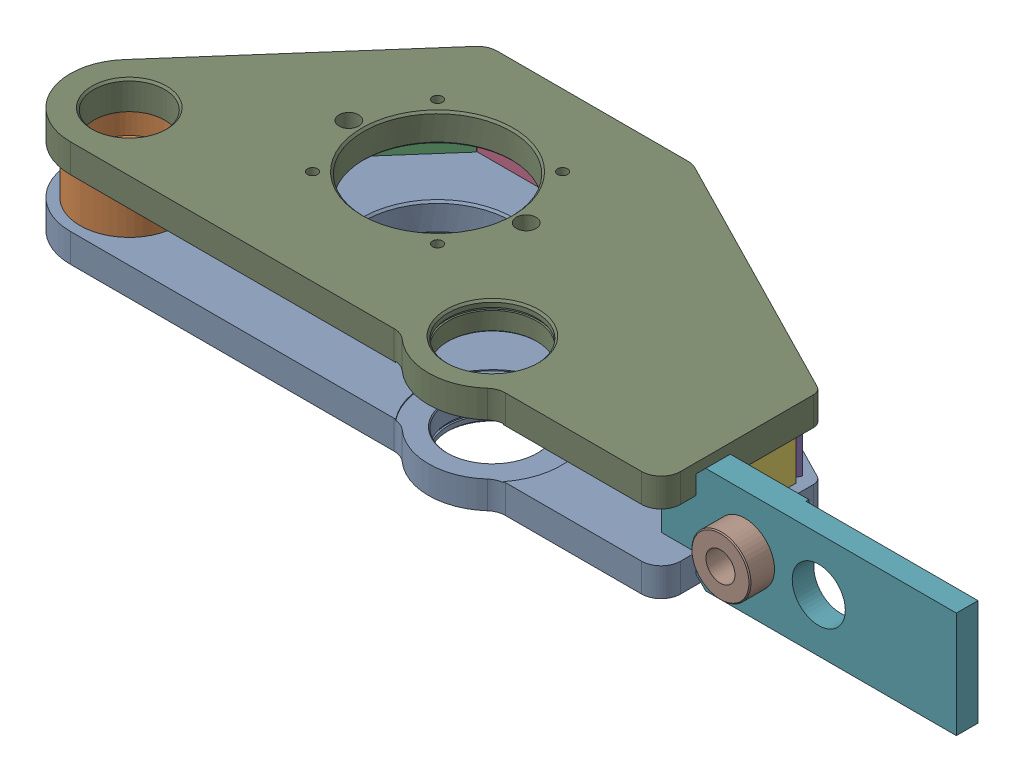
SolidWorks assembly g1_3_1_1_5_1, configuration 默认. Lengths in mm.
Overall size (926 108 318.6).
9 component instances, 9 part files, 0 mates.
Components (placement in the parent):
- g1_3_1_1_5-1_af1_1-1: g1_3_1_1_5-1_af1_1 [默认] at origin size (661 29 318.6)
- g1_3_1_1_5-2_af0_1-1: g1_3_1_1_5-2_af0_1 [默认] at (-213.2 29 0) size (100 50 100)
- g1_3_1_1_5-4_1-1: g1_3_1_1_5-4_1 [默认] at (-149.9151 54 -132.7301) x (0 1 0) z (-0.659692 0 0.751536) size (50 10 223)
- g1_3_1_1_5-5_1-1: g1_3_1_1_5-5_1 [默认] at (20.5 54 -217) x (1 0 0) z (0 1 0) size (194 10 50)
- g1_3_1_1_5-6_1-1: g1_3_1_1_5-6_1 [默认] at (248.4498 54 -161.5242) x (0 1 0) z (0.890083 0 0.455798) size (50 10 284)
- g1_3_1_1_5-7_1-1: g1_3_1_1_5-7_1 [默认] at (377.8 54 -43.9) x (0 0 -1) z (0 1 0) size (87 10 50)
- g1_3_1_1_5-9_af0_1-1: g1_3_1_1_5-9_af0_1 [默认] at (502.8 54 24.6) x (1 0 0) z (0 1 0) size (300 25 108)
- g1_3_1_1_5-8_1-1: g1_3_1_1_5-8_1 [默认] at (437.8 54 49.6) x (1 0 0) z (0 1 0) size (60 50 60)
- g1_3_1_1_5-1_af0_1-1: g1_3_1_1_5-1_af0_1 [默认] at (0 79 0) size (661 29 318.6)
